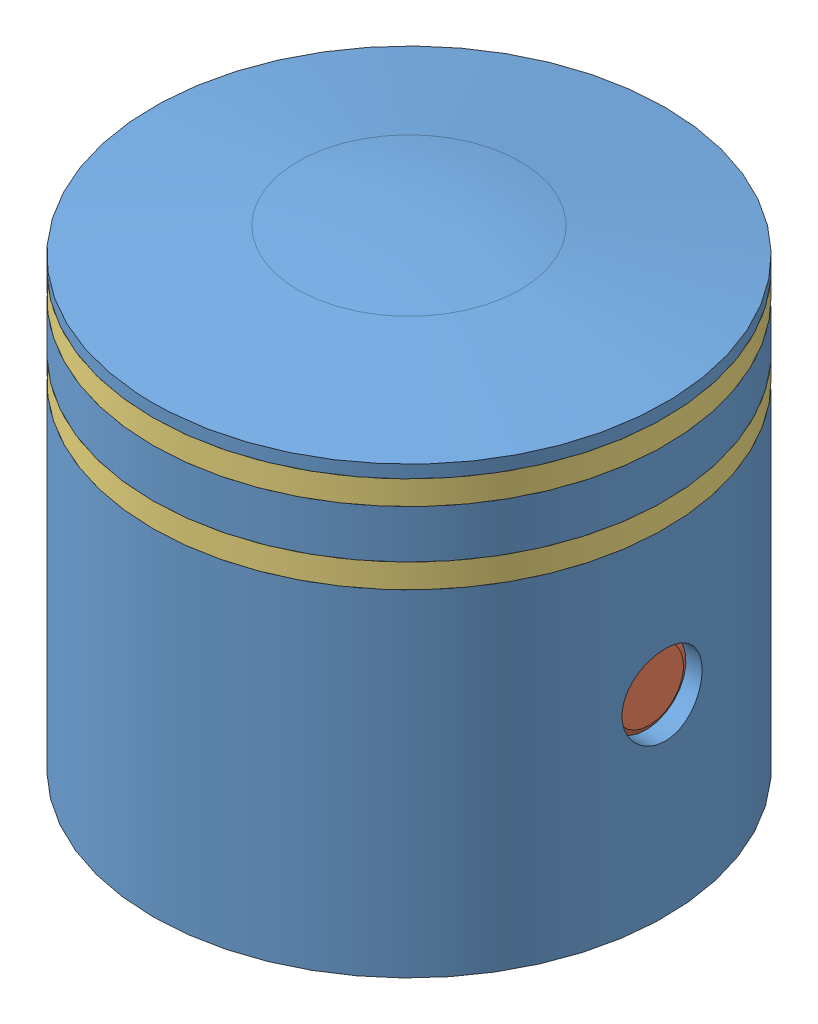
SolidWorks assembly Piston Assembly, configuration Default. Lengths in mm.
Overall size (32 30 32).
4 component instances, 3 part files, 7 mates.
Components (placement in the parent):
- #4Piston-1: #4Piston [Default] at (-5.9579 -3.7941 0) size (32 30 32)
- #5Piston Pin-1: #5Piston Pin [Default] at (9.0421 8.2059 0) x (1 0 0) z (0 0.314093 0.949392) size (30 5 5)
- #7Piston Ring-1: #7Piston Ring [Default] at (-5.9579 17.2059 0) size (32 1.5 31.97)
- #7Piston Ring-2: #7Piston Ring [Default] at (-5.9579 21.7059 0) size (32 1.5 31.97)
Mates (geometry in assembly coordinates):
- Concentric1: concentric aligned: cylinder of #4Piston-1 through (-5.9579 -3.7941 0) axis (0 -1 0) radius 14.5; cylinder of #7Piston Ring-1 through (-5.9579 18.7059 0) axis (0 -1 0) radius 16
- Coincident4: coincident anti-aligned: plane of #4Piston-1 through (8.5421 17.2059 0) normal (0 1 0); plane of #7Piston Ring-1 through (-5.9579 17.2059 0) normal (0 -1 0)
- Concentric2: concentric aligned: cylinder of #4Piston-1 through (-5.9579 -3.7941 0) axis (0 -1 0) radius 14.5; cylinder of #7Piston Ring-2 through (-5.9579 23.2059 0) axis (0 -1 0) radius 16
- Coincident5: coincident anti-aligned: plane of #4Piston-1 through (8.5421 21.7059 0) normal (0 1 0); plane of #7Piston Ring-2 through (-5.9579 21.7059 0) normal (0 -1 0)
- Coincident7: coincident aligned: plane of #4Piston-1 through (-5.9579 -3.7941 0) normal (0 0 1)
- Concentric3: concentric aligned: cylinder of #4Piston-1 through (-21.9579 8.2059 0) axis (1 0 0) radius 2.5; cylinder of #5Piston Pin-1 through (9.0421 8.2059 0) axis (1 0 0) radius 2.5
- Coincident9: coincident aligned: plane of #4Piston-1 through (-5.9579 -3.7941 0) normal (1 0 0); plane of #5Piston Pin-1 through (-5.9579 8.2059 0) normal (1 0 0)
